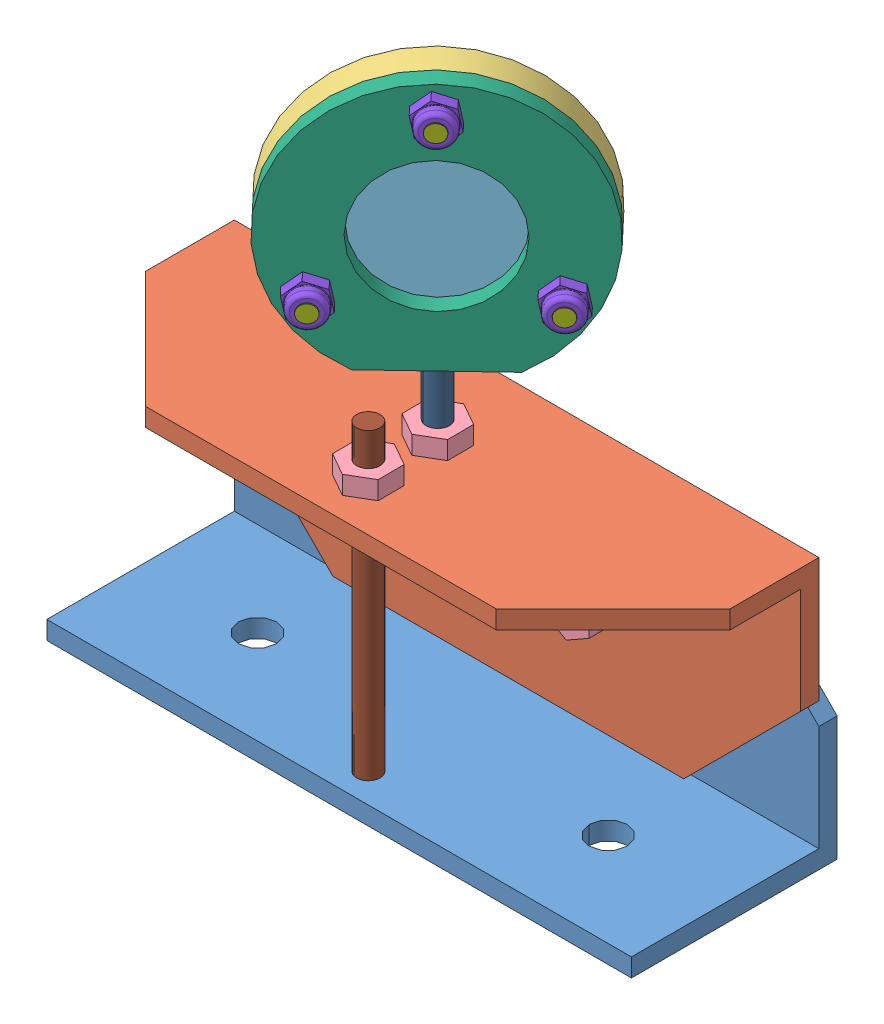
SolidWorks assembly Suporte do divisor de feixe, configuration Default. Lengths in mm.
Overall size (100 102.86 41.95).
21 component instances, 11 part files, 33 mates.
Components (placement in the parent):
- Base do divisor-1: Base do divisor [Default] at (-48.2463 -11.7326 33.4299) size (100 41.23 35.2)
- Base do divisor B-1: Base do divisor B [Default] at (51.7537 28.2674 36.5549) x (-1 0 0) z (0 0 1) size (100 41.23 35.2)
- Fixador dodivisor de feixe_frontal-1: Fixador dodivisor de feixe_frontal [Default] at (0.0337 65.5054 14.7406) x (0.688011 0 0.7257) z (-0.7257 0 0.688011) size (5 42.5 45)
- Porca M4-1: Porca M4 [Default] at (1.7537 31.3924 16.5549) size (7.78 3.12 8.95)
- Porca M4-2: Porca M4 [Default] at (1.7537 25.1424 16.5549) size (7.78 3.12 8.95)
- Divisor de feixe-1: Divisor de feixe [Default] at (1.4097 65.5054 16.192) x (0.7257 0 -0.688011) z (0.688011 0 0.7257) size (25.4 25.4 3)
- Arruela do Fixador do divisor de feixe-1: Arruela do Fixador do divisor de feixe [Default] at (3.4737 65.5054 18.3691) x (0.688011 0 0.7257) z (-0.7257 0 0.688011) size (3 42.5 45)
- Parafuso Padrao M3 10-1: Parafuso Padrao M3 10 [Default] at (-1.3424 83.5054 13.2892) x (0.7257 0 -0.688011) z (0.688011 0 0.7257) size (5.45 5.45 14)
- Porca M3-1: Porca M3 [Default] at (5.5378 83.5054 20.5462) x (0.725692 0.004853 -0.688003) z (0.003522 -0.999988 -0.003339) size (6.52 3.8 6.82)
- Parafuso Padrao M3 10-2: Parafuso Padrao M3 10 [Default] at (9.9702 56.5054 2.5642) x (-0.36285 -0.866025 0.344005) z (0.688011 0 0.7257) size (5.45 5.45 14)
- Parafuso Padrao M3 10-3: Parafuso Padrao M3 10 [Default] at (-12.6549 56.5054 24.0142) x (-0.36285 0.866025 0.344005) z (0.688011 0 0.7257) size (5.45 5.45 14)
- Porca M3-2: Porca M3 [Default] at (16.8503 56.5054 9.8212) x (-0.359796 -0.868442 0.34111) z (-0.630228 0.495791 0.597497) size (6.52 3.8 6.82)
- Porca M3-3: Porca M3 [Default] at (-5.7748 56.5054 31.2712) x (-0.365896 0.863589 0.346893) z (0.626707 0.504197 -0.594158) size (6.52 3.8 6.82)
- Parafuso Padrao M4 16-1: Parafuso Padrao M4 16 [Default] at (14.8037 8.2674 -1.7681) x (1 0 0) z (0 1 0) size (8 13 8)
- Porca M4-3: Porca M4 [Default] at (14.8037 8.2674 7.6069) x (1 0 0) z (0 1 0) size (7.78 3.12 8.95)
- Porca M4-5: Porca M4 [Default] at (-11.2963 8.2674 7.6069) x (-0.995163 -0.09824 0) z (0.09824 -0.995163 0) size (7.78 3.12 8.95)
- Parafuso Padrao M4 16-3: Parafuso Padrao M4 16 [Default] at (-11.2963 8.2674 -1.7681) x (1 0 0) z (0 1 0) size (8 13 8)
- Haste M4-2: Haste M4 [Default] at (1.7537 20.5054 16.5549) x (0.189668 0 -0.981848) z (0.981848 0 0.189668) size (4 30 4)
- Haste M4 Longa-2: Haste M4 Longa [Default] at (1.7537 -14.8576 28.4299) size (4 55 4)
- Porca M4-7: Porca M4 [Default] at (1.7537 25.1424 28.4299) size (7.78 3.12 8.95)
- Porca M4-8: Porca M4 [Default] at (1.7537 31.3924 28.4299) size (7.78 3.12 8.95)
Mates (geometry in assembly coordinates):
- Coincident1: coincident anti-aligned: plane of Base do divisor-1 through (51.7537 -11.7326 1.3569) normal (0 0 1); plane of Base do divisor B-1 through (-48.2463 28.2674 1.3569) normal (0 0 -1)
- Concentric1: concentric aligned: cylinder of Base do divisor-1 through (14.8037 8.2674 33.4299) axis (0 0 -1) radius 2; cylinder of Base do divisor B-1 through (14.8037 8.2674 36.5549) axis (0 0 -1) radius 2
- Concentric2: concentric aligned: cylinder of Base do divisor-1 through (-11.2963 8.2674 33.4299) axis (0 0 -1) radius 2; cylinder of Base do divisor B-1 through (-11.2963 8.2674 36.5549) axis (0 0 -1) radius 2
- Coincident5: coincident anti-aligned: plane of Base do divisor B-1 through (-48.2463 31.3924 36.5549) normal (0 1 0); plane of Porca M4-1 through (5.644 31.3924 18.7653) normal (0 -1 0)
- Coincident6: coincident anti-aligned: plane of Base do divisor B-1 through (-48.2463 28.2674 36.5549) normal (0 -1 0); plane of Porca M4-2 through (5.644 28.2674 18.7653) normal (0 1 0)
- Concentric6: concentric anti-aligned: circle of Fixador dodivisor de feixe_frontal-1; cylinder of Divisor de feixe-1 through (3.4737 65.5054 18.3691) axis (-0.688011 0 -0.7257) radius 12.7
- Coincident7: coincident aligned: circle of Fixador dodivisor de feixe_frontal-1; plane of Divisor de feixe-1 through (1.4097 65.5054 16.192) normal (-0.688011 0 -0.7257)
- Concentric7: concentric aligned: circle of Divisor de feixe-1; circle of Arruela do Fixador do divisor de feixe-1
- Coincident8: coincident anti-aligned: plane of Fixador dodivisor de feixe_frontal-1 through (3.4737 65.5054 18.3691) normal (0.688011 0 0.7257); plane of Arruela do Fixador do divisor de feixe-1 through (3.4737 65.5054 18.3691) normal (-0.688011 0 -0.7257)
- Concentric8: concentric aligned: cylinder of Fixador dodivisor de feixe_frontal-1 through (11.3462 56.5054 4.0156) axis (0.688011 0 0.7257) radius 1.5; circle of Arruela do Fixador do divisor de feixe-1
- Concentric9: concentric anti-aligned: circle of Fixador dodivisor de feixe_frontal-1; cylinder of Parafuso Padrao M3 10-1 through (8.2898 83.5054 23.449) axis (-0.688011 0 -0.7257) radius 1.5
- Coincident11: coincident anti-aligned: plane of Fixador dodivisor de feixe_frontal-1 through (0.0337 65.5054 14.7406) normal (-0.688011 0 -0.7257); plane of Parafuso Padrao M3 10-1 through (0.0337 83.5054 14.7406) normal (0.688011 0 0.7257)
- Concentric10: concentric anti-aligned: cylinder of Parafuso Padrao M3 10-1 through (8.2898 83.5054 23.449) axis (-0.688011 0 -0.7257) radius 1.5; cylinder of Porca M3-1 through (5.5378 83.5054 20.5462) axis (0.688011 0 0.7257) radius 1.5
- Coincident12: coincident anti-aligned: plane of Arruela do Fixador do divisor de feixe-1 through (5.5378 65.5054 20.5462) normal (0.688011 0 0.7257); plane of Porca M3-1 through (8.3626 78.9394 17.8681) normal (-0.688011 0 -0.7257)
- Concentric11: concentric aligned: circle of Base do divisor-1; cylinder of Parafuso Padrao M4 16-1 through (14.8037 8.2674 8.2319) axis (0 0 -1) radius 2
- Coincident14: coincident anti-aligned: plane of Base do divisor-1 through (51.7537 -11.7326 -1.7681) normal (0 0 -1); plane of Parafuso Padrao M4 16-1 through (14.8037 8.2674 -1.7681) normal (0 0 1)
- Concentric12: concentric anti-aligned: cylinder of Parafuso Padrao M4 16-1 through (14.8037 8.2674 8.2319) axis (0 0 -1) radius 2; cylinder of Porca M4-3 through (14.8037 8.2674 4.4819) axis (0 0 1) radius 2
- Coincident15: coincident anti-aligned: plane of Base do divisor B-1 through (-48.2463 28.2674 4.4819) normal (0 0 1); plane of Porca M4-3
- Concentric13: concentric aligned: axis of Base do divisor-1 through (-11.2963 8.2674 1.3569) axis (0 0 -1); cylinder of Parafuso Padrao M4 16-3 through (-11.2963 8.2674 8.2319) axis (0 0 -1) radius 2
- Coincident17: coincident anti-aligned: plane of Base do divisor-1 through (51.7537 -11.7326 -1.7681) normal (0 0 -1); plane of Parafuso Padrao M4 16-3 through (-11.2963 8.2674 -1.7681) normal (0 0 1)
- Concentric14: concentric anti-aligned: axis of Porca M4-5 through (-11.2963 8.2674 4.4819) axis (0 0 1); cylinder of Parafuso Padrao M4 16-3 through (-11.2963 8.2674 8.2319) axis (0 0 -1) radius 2
- Coincident19: coincident anti-aligned: plane of Base do divisor B-1 through (-48.2463 28.2674 4.4819) normal (0 0 1); plane of Porca M4-5
- Concentric16: concentric anti-aligned: cylinder of Base do divisor B-1 through (1.7537 31.3924 16.5549) axis (0 -1 0) radius 2; circle of Haste M4-2
- Coincident21: coincident anti-aligned: plane of Fixador dodivisor de feixe_frontal-1 through (1.7537 50.5054 16.5549) normal (0 -1 0); circle of Haste M4-2
- Concentric17: concentric: moEndPointRef_w of Porca M4-1; cylinder of Haste M4-2 through (1.7537 50.5054 16.5549) axis (0 -1 0) radius 2
- Coincident23: coincident aligned: plane of Base do divisor-1; plane of Haste M4 Longa-2 through (1.7537 -14.8576 28.4299) normal (0 -1 0)
- Concentric18: concentric anti-aligned: cylinder of Base do divisor-1 through (1.7537 -14.8576 28.4299) axis (0 1 0) radius 2; cylinder of Haste M4 Longa-2 through (1.7537 40.1424 28.4299) axis (0 -1 0) radius 2
- Concentric19: concentric aligned: cylinder of Porca M4-2 through (1.7537 28.2674 16.5549) axis (0 -1 0) radius 2; cylinder of Haste M4-2 through (1.7537 50.5054 16.5549) axis (0 -1 0) radius 2
- Concentric20: concentric aligned: cylinder of Fixador dodivisor de feixe_frontal-1 through (1.7537 50.5054 16.5549) axis (0 -1 0) radius 2; cylinder of Haste M4-2 through (1.7537 50.5054 16.5549) axis (0 -1 0) radius 2
- Concentric21: concentric aligned: cylinder of Haste M4 Longa-2 through (1.7537 40.1424 28.4299) axis (0 -1 0) radius 2; cylinder of Porca M4-8 through (1.7537 34.5174 28.4299) axis (0 -1 0) radius 2
- Concentric22: concentric aligned: cylinder of Haste M4 Longa-2 through (1.7537 40.1424 28.4299) axis (0 -1 0) radius 2; cylinder of Porca M4-7 through (1.7537 28.2674 28.4299) axis (0 -1 0) radius 2
- Coincident25: coincident anti-aligned: plane of Base do divisor B-1 through (-48.2463 28.2674 36.5549) normal (0 -1 0); plane of Porca M4-7 through (5.644 28.2674 30.6403) normal (0 1 0)
- Coincident26: coincident anti-aligned: plane of Base do divisor B-1 through (-48.2463 31.3924 36.5549) normal (0 1 0); plane of Porca M4-8 through (5.644 31.3924 30.6403) normal (0 -1 0)
